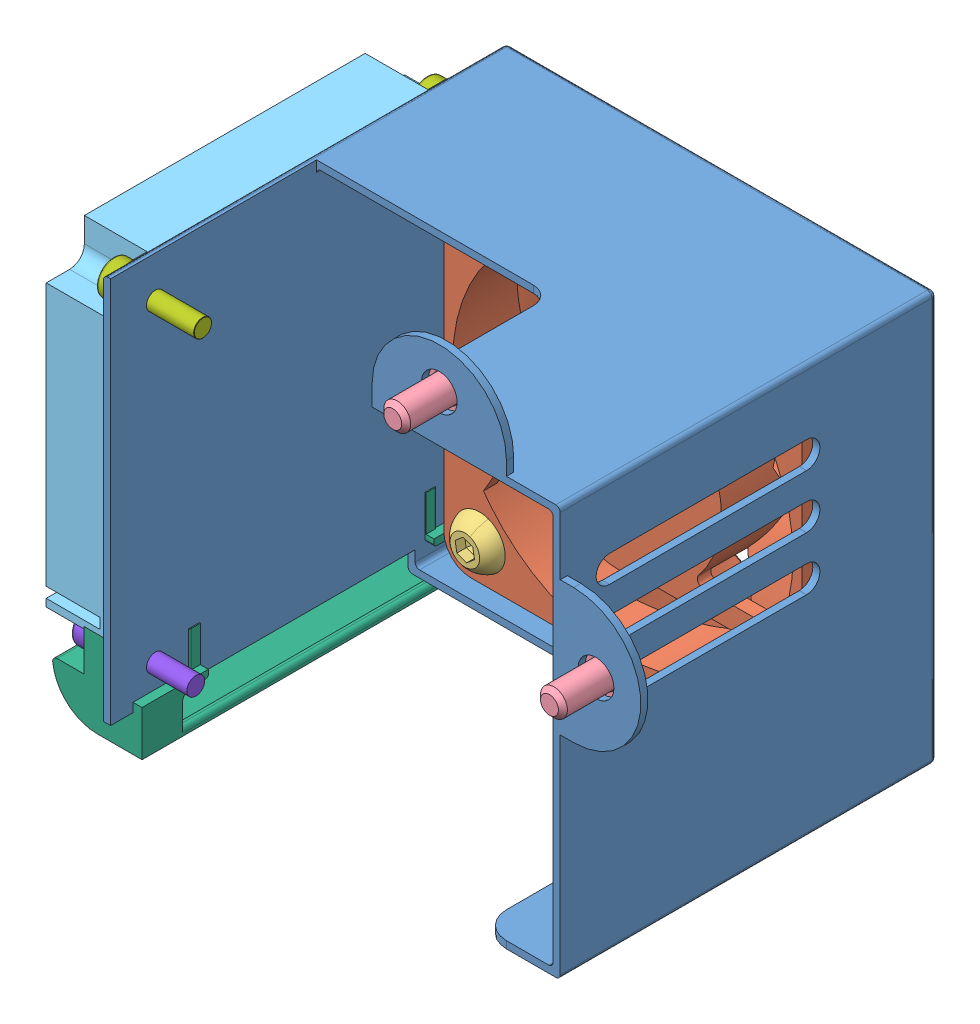
SolidWorks assembly Fan assembly, configuration 默认. Lengths in mm.
Overall size (68 56.25 64.99).
14 component instances, 8 part files, 29 mates.
Components (placement in the parent):
- Fan cover-1: Fan cover [默认] at (-7.2556 -5.6637 34.5) size (57 54.7 45)
- Nozzle fan-1: Nozzle fan [默认] at (-17.5818 -113.0555 17.8974) x (0 1 0) z (0.819152 0 -0.573576) size (40 31.13 38.5)
- M3X10 Pan Head Screw-1: M3X10 Pan Head Screw [默认] at (-24.7556 11.1363 47.15) x (0 0 -1) z (-0.985439 0.170027 0) size (11.75 5.7 5.7)
- M3X10 Pan Head Screw-2: M3X10 Pan Head Screw [默认] at (-24.7556 -20.8637 47.15) x (0 0 -1) z (0.939022 -0.343858 0) size (11.75 5.7 5.7)
- M3X10 Pan Head Screw-3: M3X10 Pan Head Screw [默认] at (7.2444 11.1363 47.15) x (0 0 -1) z (0.999934 -0.011494 0) size (11.75 5.7 5.7)
- M3X10 Pan Head Screw-4: M3X10 Pan Head Screw [默认] at (7.2444 -20.8637 47.15) x (0 0 -1) z (-0.994747 -0.102361 0) size (11.75 5.7 5.7)
- M3X6Pan Head Screw-1: M3X6Pan Head Screw [默认] at (1.7444 22.3363 74.05) x (0 0 1) z (-1 0 0) size (7.65 5.7 5.7)
- M3X6Pan Head Screw-2: M3X6Pan Head Screw [默认] at (19.2444 3.4363 74.05) x (0 0 1) z (-1 0 0) size (7.65 5.7 5.7)
- Cold section fan-1: Cold section fan [默认] at (209.4666 59.8363 -132.7778) x (-1 0 0) z (0 1 0) size (11 40 40)
- Nozzle fan duct-1: Nozzle fan duct [默认] at (-35.9445 -24.2637 57) x (0 0 1) z (0 1 0) size (40 9.98 9.65)
- M2X8 Socket Head Screw-1: M2X8 Socket Head Screw [默认] at (-34.6445 13.3363 39.5) size (10 3.8 3.8)
- M2X8 Socket Head Screw-2: M2X8 Socket Head Screw [默认] at (-34.6445 13.3363 74.5) size (10 3.8 3.8)
- M2X10杯头-1: M2X10杯头 [默认] at (-37.4445 -21.6637 39.5) size (12 3.8 3.8)
- M2X10杯头-2: M2X10杯头 [默认] at (-37.4445 -21.6637 74.5) size (12 3.8 3.8)
Mates (geometry in assembly coordinates):
- 同心1: concentric aligned: cylinder of Fan cover-1 through (7.2444 11.1363 37.7) axis (0 0 -1) radius 2.7; cylinder of Nozzle fan-1 through (7.2444 11.1363 45.5) axis (0 0 -1) radius 1.6
- 同心2: concentric aligned: cylinder of Nozzle fan-1 through (7.2444 -20.8637 45.5) axis (0 0 -1) radius 1.6; cylinder of Fan cover-1 through (7.2444 -20.8637 37.7) axis (0 0 -1) radius 2.7
- 同心6: concentric anti-aligned: cylinder of Nozzle fan-1 through (7.2444 11.1363 45.5) axis (0 0 -1) radius 1.6; cylinder of M3X10 Pan Head Screw-3 through (7.2444 11.1363 39.5) axis (0 0 1) radius 1.5
- 同心7: concentric anti-aligned: cylinder of Nozzle fan-1 through (7.2444 -20.8637 45.5) axis (0 0 -1) radius 1.6; cylinder of M3X10 Pan Head Screw-4 through (7.2444 -20.8637 39.5) axis (0 0 1) radius 1.5
- 同心8: concentric anti-aligned: cylinder of Nozzle fan-1 through (-24.7556 -20.8637 45.5) axis (0 0 -1) radius 1.6; cylinder of M3X10 Pan Head Screw-2 through (-24.7556 -20.8637 39.5) axis (0 0 1) radius 1.5
- 同心9: concentric anti-aligned: cylinder of Nozzle fan-1 through (-24.7556 11.1363 45.5) axis (0 0 -1) radius 1.6; cylinder of M3X10 Pan Head Screw-1 through (-24.7556 11.1363 39.5) axis (0 0 1) radius 1.5
- 重合1: coincident anti-aligned: plane of Fan cover-1 through (7.2444 -20.8637 39.5) normal (0 0 1); plane of Nozzle fan-1 through (7.2444 -20.8637 39.5) normal (0 0 -1)
- 同心10: concentric anti-aligned: cylinder of Nozzle fan-1 through (7.2444 -20.8637 45.5) axis (0 0 -1) radius 1.6; cylinder of M3X10 Pan Head Screw-4 through (7.2444 -20.8637 39.5) axis (0 0 1) radius 1.5
- 同心11: concentric anti-aligned: cylinder of Nozzle fan-1 through (-24.7556 -20.8637 45.5) axis (0 0 -1) radius 1.6; cylinder of M3X10 Pan Head Screw-2 through (-24.7556 -20.8637 39.5) axis (0 0 1) radius 1.5
- 同心12: concentric anti-aligned: cylinder of Nozzle fan-1 through (7.2444 11.1363 45.5) axis (0 0 -1) radius 1.6; cylinder of M3X10 Pan Head Screw-3 through (7.2444 11.1363 39.5) axis (0 0 1) radius 1.5
- 同心13: concentric anti-aligned: cylinder of Nozzle fan-1 through (-24.7556 11.1363 45.5) axis (0 0 -1) radius 1.6; cylinder of M3X10 Pan Head Screw-1 through (-24.7556 11.1363 39.5) axis (0 0 1) radius 1.5
- 重合2: coincident anti-aligned: plane of Nozzle fan-1 through (-8.7556 -4.8637 45.5) normal (0 0 1); plane of M3X10 Pan Head Screw-2 through (-24.7556 -20.8637 45.5) normal (0 0 -1)
- 重合3: coincident anti-aligned: plane of Nozzle fan-1 through (-8.7556 -4.8637 45.5) normal (0 0 1); plane of M3X10 Pan Head Screw-1 through (-24.7556 11.1363 45.5) normal (0 0 -1)
- 重合4: coincident anti-aligned: plane of Nozzle fan-1 through (-8.7556 -4.8637 45.5) normal (0 0 1); plane of M3X10 Pan Head Screw-4 through (7.2444 -20.8637 45.5) normal (0 0 -1)
- 重合5: coincident anti-aligned: plane of Nozzle fan-1 through (-8.7556 -4.8637 45.5) normal (0 0 1); plane of M3X10 Pan Head Screw-3 through (7.2444 11.1363 45.5) normal (0 0 -1)
- 重合6: coincident anti-aligned: plane of Fan cover-1 through (-32.7556 -5.6637 34.5) normal (-1 0 0); plane of Cold section fan-1 through (-32.7556 -4.1637 57) normal (1 0 0)
- 同心14: concentric aligned: cylinder of Fan cover-1 through (-31.7556 13.3363 39.5) axis (-1 0 0) radius 1; cylinder of Cold section fan-1 through (-31.8667 13.3363 39.5) axis (-1 0 0) radius 1.3
- 同心15: concentric aligned: cylinder of Fan cover-1 through (-31.7556 -21.6637 39.5) axis (-1 0 0) radius 1; cylinder of Cold section fan-1 through (-31.8667 -21.6637 39.5) axis (-1 0 0) radius 1.3
- 重合7: coincident anti-aligned: plane of Cold section fan-1 through (-34.6445 -21.422 39.6146) normal (-1 0 0); plane of Nozzle fan duct-1 through (-34.6445 -24.2637 57) normal (1 0 0)
- 同心16: concentric aligned: cylinder of Cold section fan-1 through (-31.8667 -21.6637 39.5) axis (-1 0 0) radius 1.3; cylinder of Nozzle fan duct-1 through (-30.2945 -21.6637 39.5) axis (-1 0 0) radius 1.2
- 同心17: concentric aligned: cylinder of Fan cover-1 through (-31.7556 -21.6637 74.5) axis (-1 0 0) radius 1; cylinder of Nozzle fan duct-1 through (-30.2945 -21.6637 74.5) axis (-1 0 0) radius 1.2
- 同心18: concentric aligned: cylinder of Cold section fan-1 through (-31.8667 13.3363 74.5) axis (-1 0 0) radius 1.3; cylinder of M2X8 Socket Head Screw-2 through (-35.1442 13.3363 74.5) axis (-1 0 0) radius 1
- 重合8: coincident anti-aligned: plane of Cold section fan-1 through (-34.6445 13.0945 74.3854) normal (-1 0 0); plane of M2X8 Socket Head Screw-2 through (-34.6445 15.2363 74.5) normal (1 0 0)
- 同心19: concentric aligned: cylinder of Cold section fan-1 through (-31.8667 13.3363 39.5) axis (-1 0 0) radius 1.3; cylinder of M2X8 Socket Head Screw-1 through (-35.1442 13.3363 39.5) axis (-1 0 0) radius 1
- 重合9: coincident anti-aligned: plane of Cold section fan-1 through (-34.6445 13.2216 39.7418) normal (-1 0 0); plane of M2X8 Socket Head Screw-1 through (-34.6445 15.2363 39.5) normal (1 0 0)
- 同心20: concentric aligned: cylinder of Nozzle fan duct-1 through (-30.2945 -21.6637 39.5) axis (-1 0 0) radius 1.2; cylinder of M2X10杯头-1 through (-37.9442 -21.6637 39.5) axis (-1 0 0) radius 1
- 重合10: coincident aligned: plane of Nozzle fan duct-1 through (-37.4445 -24.2637 57) normal (-1 0 0); circle of M2X10杯头-1
- 同心21: concentric aligned: cylinder of Nozzle fan duct-1 through (-30.2945 -21.6637 74.5) axis (-1 0 0) radius 1.2; cylinder of M2X10杯头-2 through (-37.9442 -21.6637 74.5) axis (-1 0 0) radius 1
- 重合11: coincident anti-aligned: plane of Nozzle fan duct-1 through (-37.4445 -24.2637 57) normal (-1 0 0); plane of M2X10杯头-2 through (-37.4445 -19.7637 74.5) normal (1 0 0)
